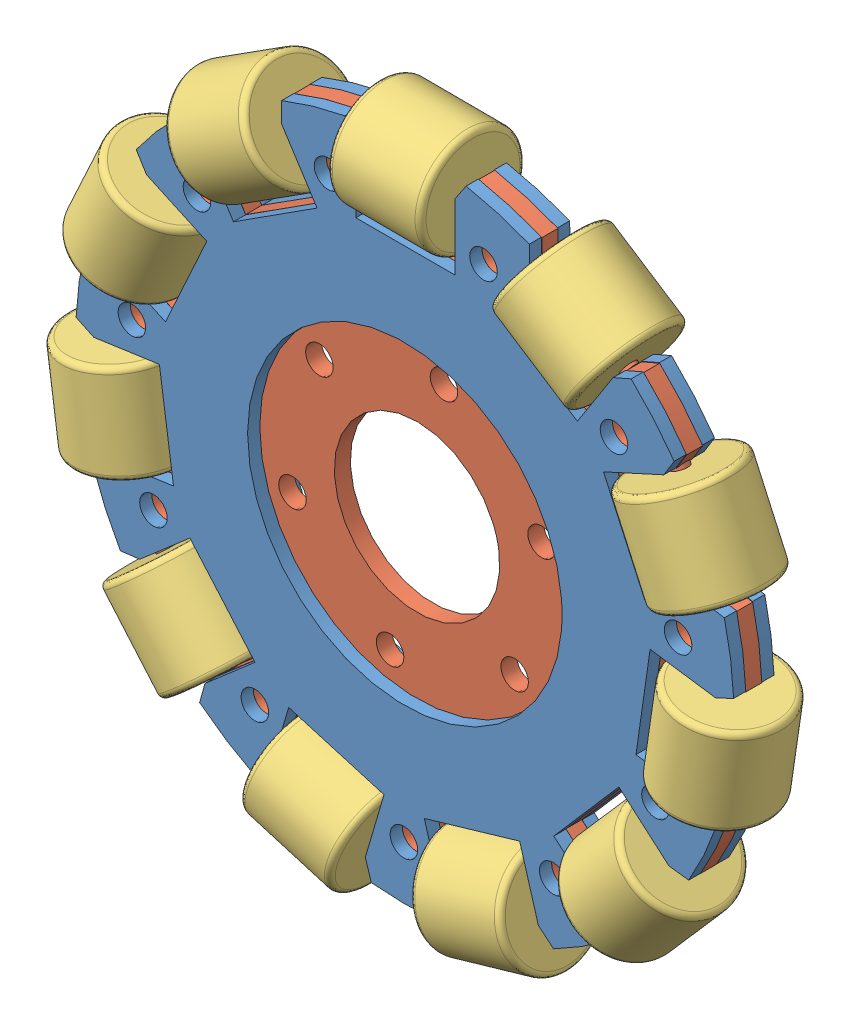
SolidWorks assembly omni wheel 127mm 1, configuration 預設. Lengths in mm.
Overall size (147.34 146.72 26.77).
14 component instances, 3 part files, 11 mates.
Components (placement in the parent):
- Part1-1: Part1 [Default] at (0 0 5.11) size (119.14 118.25 2.21)
- Part3-1: Part3 [Default] at (0 0 2.21) x (0.960473 0.278374 0) z (0 0 1) size (119.14 118.23 2.9)
- Part1-2: Part1 [Default] at origin size (119.14 118.25 2.21)
- Part4-1: Part4 [Default] at (-22.2066 50.6262 3.66) x (0.34688 -0.54389 0.764106) z (-0.843122 -0.537723 0) size (19 19 17)
- Part4-2: Part4 [Default] at (-46.0519 30.5837 3.66) x (0.585863 -0.270012 0.764106) z (-0.418564 -0.908187 0) size (19 19 17)
- Part4-3: Part4 [Default] at (-55.2761 0.8311 3.66) x (0.638839 0.089593 0.764106) z (0.138884 -0.990309 0) size (19 19 17)
- Part4-4: Part4 [Default] at (-46.9505 -29.1854 3.66) x (0.488988 0.420753 0.764106) z (0.652238 -0.758014 0) size (19 19 17)
- Part4-5: Part4 [Default] at (-23.7185 -49.9357 3.66) x (0.183887 0.618327 0.764106) z (0.958511 -0.285056 0) size (19 19 17)
- Part4-6: Part4 [Default] at (7.044 -54.8318 3.66) x (-0.179597 0.619586 0.764106) z (0.960463 0.278406 0) size (19 19 17)
- Part4-7: Part4 [Default] at (35.5701 -42.3191 3.66) x (-0.48606 0.424131 0.764106) z (0.657476 0.753476 0) size (19 19 17)
- Part4-8: Part4 [Default] at (52.8029 -16.3705 3.66) x (-0.638203 0.094018 0.764106) z (0.145744 0.989322 0) size (19 19 17)
- Part4-9: Part4 [Default] at (53.2712 14.7757 3.66) x (-0.58772 -0.265946 0.764106) z (-0.412261 0.911066 0) size (19 19 17)
- Part4-10: Part4 [Default] at (36.8262 41.2307 3.66) x (-0.350641 -0.541473 0.764106) z (-0.839375 0.543553 0) size (19 19 17)
- Part4-11: Part4 [Default] at (8.6892 54.5952 3.66) x (-0.002235 -0.645087 0.764106) z (-0.999994 0.003465 0) size (19 19 17)
Mates (geometry in assembly coordinates):
- 重合/共線/共點1: coincident anti-aligned: plane of Part1-1 through (0 10.239 5.11) normal (0 0 -1); plane of Part3-1 through (0 10.239 5.11) normal (0 0 1)
- 同軸心1: concentric aligned: circle of Part1-1; circle of Part3-1
- 重合/共線/共點5: coincident anti-aligned: plane of Part3-1 through (0 10.239 2.21) normal (0 0 -1); plane of Part1-2 through (0 10.239 2.21) normal (0 0 1)
- 同軸心2: concentric aligned: circle of Part3-1; circle of Part1-2
- 同軸心3: concentric aligned: cylinder of Part1-1 through (14.2544 58.1641 5.11) axis (0 0 1) radius 2.5; cylinder of Part3-1 through (14.2544 58.1641 2.21) axis (0 0 1) radius 2.5
- 同軸心4: concentric aligned: cylinder of Part3-1 through (14.2544 58.1641 2.21) axis (0 0 1) radius 2.5; cylinder of Part1-2 through (14.2544 58.1641 0) axis (0 0 1) radius 2.5
- 同軸心5: concentric anti-aligned: cylinder of Part3-1 through (-37.8043 50.9173 3.66) axis (0.843122 0.537723 0) radius 1.45; cylinder of Part4-1 through (-22.2066 60.8652 3.66) axis (-0.843122 -0.537723 0) radius 1.45
- 平行相距1: distance = 0.5 mm anti-aligned: plane of Part4-1 through (-22.2066 50.6262 3.66) normal (0.843122 0.537723 0); plane of Part3-1 through (-15.87 41.6207 5.11) normal (-0.843122 -0.537723 0)
- 重合/共線/共點6: coincident anti-aligned: plane of Part1-2 through (0 10.239 0) normal (0 0 -1)
- 重合/共線/共點7: coincident aligned: plane of Part1-1 through (0 10.239 5.11) normal (1 0 0)
- 重合/共線/共點8: coincident aligned: plane of Part1-1 through (0 0 5.11) normal (0 1 0)
